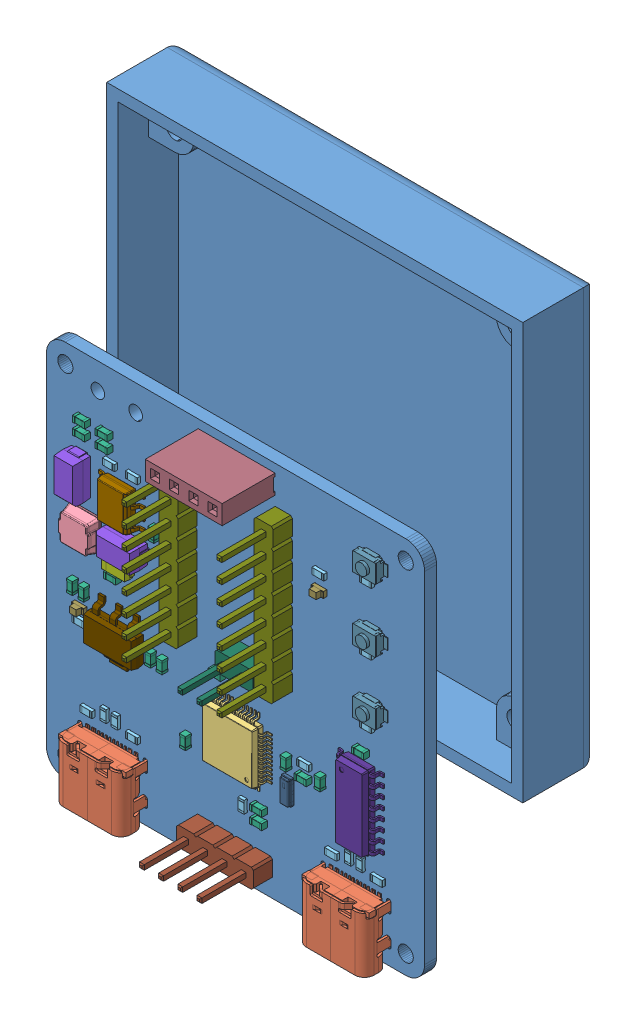
SolidWorks assembly 装配体1, configuration 默认. Lengths in mm.
Overall size (90.8 71.29 67.36).
116 component instances, 19 part files, 0 mates.
Components (placement in the parent):
- Shiled_Bottom-1: Shiled_Bottom [默认] at (-2.6606 -0.7391 50) size (55 55 10)
- TMC2209_TestBoard-2: TMC2209_TestBoard [默认] at (-65.2006 82.5018 107.1928) size (50 50 11.64)
  - TMC2209_TestBoard.step-1: TMC2209_TestBoard.step [默认] at origin size (50 50 11.64)
    - USB_C_Receptacle_GCT_USB4105-xx-A_16P_TopMnt_Horizontal.step-1: USB_C_Receptacle_GCT_USB4105-xx-A_16P_TopMnt_Horizontal.step [默认] at (84.5999 -85.7499 1.63) size (8.94 7.78 4.26)
      - COMPOUND.step-1: COMPOUND.step [默认] at origin size (8.94 7.78 4.26)
    - LQFP-48_7x7mm_P0.5mm.step-1: LQFP-48_7x7mm_P0.5mm.step [默认] at (101.2699 -73.4399 1.63) x (-1 0 0) z (0 0 1) size (9 9 1.5)
      - SOLID.step-1: SOLID.step [默认] at origin size (9 9 1.5)
    - L_Bourns-SRN4018.step-1: L_Bourns-SRN4018.step [默认] at (81.2119 -59.0749 1.63) x (0 -1 0) z (0 0 1) size (4 4.09 1.8)
      - COMPOUND-0.step-1: COMPOUND-0.step [默认] at origin size (4 4.09 1.8)
    - R_0603_1608Metric.step-1: R_0603_1608Metric.step [默认] at (118.4749 -54.7599 1.63) x (-1 0 0) z (0 0 1) size (1.6 0.8 0.45)
      - SOLID-1.step-1: SOLID-1.step [默认] at origin size (1.6 0.8 0.45)
    - C_0603_1608Metric.step-1: C_0603_1608Metric.step [默认] at (80.9149 -46.8999 1.63) x (-1 0 0) z (0 0 1) size (1.6 0.8 0.8)
      - SOLID-2.step-1: SOLID-2.step [默认] at origin size (1.6 0.8 0.8)
    - CP_EIA-3216-10_Kemet-I.step-1: CP_EIA-3216-10_Kemet-I.step [默认] at (85.8749 -60.8899 1.63) size (3.4 1.8 1.2)
      - SOLID-3.step-1: SOLID-3.step [默认] at origin size (3.4 1.8 1.2)
    - C_0603_1608Metric.step-2: C_0603_1608Metric.step [默认] at (90.4899 -55.0149 1.63) x (0 1 0) z (0 0 1) size (1.6 0.8 0.8)
      - SOLID-2.step-1: SOLID-2.step [默认] at origin size (1.6 0.8 0.8)
    - SS54.step-1: SS54.step [默认] at (86.9299 -58.1799 1.63) size (5.1 2.6 2.45)
      - COMPOUND-4.step-1: COMPOUND-4.step [默认] at origin size (5.1 2.6 2.45)
    - TPS5450DDAR.step-1: TPS5450DDAR.step [默认] at (85.9819 -53.7349 1.63) x (-1 0 0) z (0 0 1) size (6.03 4.9 1.57)
      - COMPOUND-5.step-1: COMPOUND-5.step [默认] at origin size (6.03 4.9 1.57)
    - CSTCE8M00G55-R0.step-1: CSTCE8M00G55-R0.step [默认] at (107.9443 -75.8125 1.63) x (0 -1 0) z (-1 0 0) size (3.2 0.7 1.3)
      - COMPOUND-6.step-1: COMPOUND-6.step [默认] at origin size (3.2 0.7 1.3)
    - PinHeader_1x04_P2.54mm_Vertical.step-1: PinHeader_1x04_P2.54mm_Vertical.step [默认] at (96.8849 -85.9399 1.63) x (0 1 0) z (0 0 1) size (2.54 10.16 11.54)
      - SOLID-7.step-1: SOLID-7.step [默认] at origin size (2.54 10.16 11.54)
    - LED_0603_1608Metric.step-1: LED_0603_1608Metric.step [默认] at (80.4824 -68.6399 1.63) size (1.6 0.8 1.1)
      - SOLID-8.step-1: SOLID-8.step [默认] at origin size (1.6 0.8 1.1)
    - R_0603_1608Metric.step-2: R_0603_1608Metric.step [默认] at (119.9149 -80.0649 1.63) x (-1 0 0) z (0 0 1) size (1.6 0.8 0.45)
      - SOLID-1.step-1: SOLID-1.step [默认] at origin size (1.6 0.8 0.45)
    - C_0603_1608Metric.step-3: C_0603_1608Metric.step [默认] at (83.9049 -46.8999 1.63) size (1.6 0.8 0.8)
      - SOLID-2.step-1: SOLID-2.step [默认] at origin size (1.6 0.8 0.8)
    - R_0603_1608Metric.step-3: R_0603_1608Metric.step [默认] at (84.5299 -50.1499 1.63) size (1.6 0.8 0.45)
      - SOLID-1.step-1: SOLID-1.step [默认] at origin size (1.6 0.8 0.45)
    - R_0603_1608Metric.step-4: R_0603_1608Metric.step [默认] at (116.1499 -79.3149 1.63) x (0 -1 0) z (0 0 1) size (1.6 0.8 0.45)
      - SOLID-1.step-1: SOLID-1.step [默认] at origin size (1.6 0.8 0.45)
    - PinSocket_1x04_P2.54mm_Vertical.step-1: PinSocket_1x04_P2.54mm_Vertical.step [默认] at (104.8499 -41.7899 1.63) x (0 -1 0) z (0 0 1) size (2.54 10.16 10.1)
      - SOLID-9.step-1: SOLID-9.step [默认] at origin size (2.54 10.16 10.1)
    - C_0603_1608Metric.step-4: C_0603_1608Metric.step [默认] at (79.7199 -66.3699 1.63) x (0 -1 0) z (0 0 1) size (1.6 0.8 0.8)
      - SOLID-2.step-1: SOLID-2.step [默认] at origin size (1.6 0.8 0.8)
    - B3U-1000P.step-1: B3U-1000P.step [默认] at (119.0699 -60.9299 1.63) x (1 0 0) z (0 -1 0) size (4 1.6 2.5)
      - SOLID-10.step-1: SOLID-10.step [默认] at origin size (4 1.6 2.5)
    - R_0603_1608Metric.step-5: R_0603_1608Metric.step [默认] at (102.0399 -80.4249 1.63) x (0 1 0) z (0 0 1) size (1.6 0.8 0.45)
      - SOLID-1.step-1: SOLID-1.step [默认] at origin size (1.6 0.8 0.45)
    - C_0603_1608Metric.step-5: C_0603_1608Metric.step [默认] at (81.2299 -66.3699 1.63) x (0 -1 0) z (0 0 1) size (1.6 0.8 0.8)
      - SOLID-2.step-1: SOLID-2.step [默认] at origin size (1.6 0.8 0.8)
    - SS54.step-2: SS54.step [默认] at (80.5699 -53.0799 1.63) x (0 1 0) z (0 0 1) size (5.1 2.6 2.45)
      - COMPOUND-4.step-1: COMPOUND-4.step [默认] at origin size (5.1 2.6 2.45)
    - B3U-1000P.step-2: B3U-1000P.step [默认] at (119.0699 -52.6099 1.63) x (1 0 0) z (0 -1 0) size (4 1.6 2.5)
      - SOLID-10.step-1: SOLID-10.step [默认] at origin size (4 1.6 2.5)
    - R_0603_1608Metric.step-6: R_0603_1608Metric.step [默认] at (110.2049 -71.7199 1.63) x (-1 0 0) z (0 0 1) size (1.6 0.8 0.45)
      - SOLID-1.step-1: SOLID-1.step [默认] at origin size (1.6 0.8 0.45)
    - R_0603_1608Metric.step-7: R_0603_1608Metric.step [默认] at (81.5499 -79.9199 1.63) size (1.6 0.8 0.45)
      - SOLID-1.step-1: SOLID-1.step [默认] at origin size (1.6 0.8 0.45)
    - LED_0603_1608Metric.step-2: LED_0603_1608Metric.step [默认] at (112.1799 -50.8199 1.63) x (-1 0 0) z (0 0 1) size (1.6 0.8 1.1)
      - SOLID-8.step-1: SOLID-8.step [默认] at origin size (1.6 0.8 1.1)
    - R_0603_1608Metric.step-8: R_0603_1608Metric.step [默认] at (80.4699 -70.1499 1.63) x (-1 0 0) z (0 0 1) size (1.6 0.8 0.45)
      - SOLID-1.step-1: SOLID-1.step [默认] at origin size (1.6 0.8 0.45)
    - C_0603_1608Metric.step-6: C_0603_1608Metric.step [默认] at (110.2049 -73.2199 1.63) size (1.6 0.8 0.8)
      - SOLID-2.step-1: SOLID-2.step [默认] at origin size (1.6 0.8 0.8)
    - PinHeader_1x02_P2.54mm_Vertical.step-1: PinHeader_1x02_P2.54mm_Vertical.step [默认] at (101.9599 -63.3799 1.63) x (0 1 0) z (0 0 1) size (2.54 5.08 11.54)
      - SOLID-11.step-1: SOLID-11.step [默认] at origin size (2.54 5.08 11.54)
    - USB_C_Receptacle_GCT_USB4105-xx-A_16P_TopMnt_Horizontal.step-2: USB_C_Receptacle_GCT_USB4105-xx-A_16P_TopMnt_Horizontal.step [默认] at (116.7699 -85.7499 1.63) size (8.94 7.78 4.26)
      - COMPOUND.step-1: COMPOUND.step [默认] at origin size (8.94 7.78 4.26)
    - C_0603_1608Metric.step-7: C_0603_1608Metric.step [默认] at (107.9499 -72.4699 1.63) x (0 -1 0) z (0 0 1) size (1.6 0.8 0.8)
      - SOLID-2.step-1: SOLID-2.step [默认] at origin size (1.6 0.8 0.8)
    - C_0603_1608Metric.step-8: C_0603_1608Metric.step [默认] at (91.5699 -69.5099 1.63) x (0 1 0) z (0 0 1) size (1.6 0.8 0.8)
      - SOLID-2.step-1: SOLID-2.step [默认] at origin size (1.6 0.8 0.8)
    - PinHeader_1x08_P2.54mm_Vertical.step-1: PinHeader_1x08_P2.54mm_Vertical.step [默认] at (94.5549 -63.3799 1.63) x (-1 0 0) z (0 0 1) size (2.54 20.32 11.54)
      - SOLID-12.step-1: SOLID-12.step [默认] at origin size (2.54 20.32 11.54)
    - C_0603_1608Metric.step-9: C_0603_1608Metric.step [默认] at (117.8149 -66.3699 1.63) x (-1 0 0) z (0 0 1) size (1.6 0.8 0.8)
      - SOLID-2.step-1: SOLID-2.step [默认] at origin size (1.6 0.8 0.8)
    - PinHeader_1x08_P2.54mm_Vertical.step-2: PinHeader_1x08_P2.54mm_Vertical.step [默认] at (107.1449 -45.5999 1.63) size (2.54 20.32 11.54)
      - SOLID-12.step-1: SOLID-12.step [默认] at origin size (2.54 20.32 11.54)
    - R_0603_1608Metric.step-9: R_0603_1608Metric.step [默认] at (118.4749 -46.5499 1.63) x (-1 0 0) z (0 0 1) size (1.6 0.8 0.45)
      - SOLID-1.step-1: SOLID-1.step [默认] at origin size (1.6 0.8 0.45)
    - C_0603_1608Metric.step-10: C_0603_1608Metric.step [默认] at (94.6599 -76.6499 1.63) x (0 1 0) z (0 0 1) size (1.6 0.8 0.8)
      - SOLID-2.step-1: SOLID-2.step [默认] at origin size (1.6 0.8 0.8)
    - R_0603_1608Metric.step-10: R_0603_1608Metric.step [默认] at (87.5549 -79.9199 1.63) x (-1 0 0) z (0 0 1) size (1.6 0.8 0.45)
      - SOLID-1.step-1: SOLID-1.step [默认] at origin size (1.6 0.8 0.45)
    - R_0603_1608Metric.step-11: R_0603_1608Metric.step [默认] at (83.7999 -79.1699 1.63) x (0 -1 0) z (0 0 1) size (1.6 0.8 0.45)
      - SOLID-1.step-1: SOLID-1.step [默认] at origin size (1.6 0.8 0.45)
    - R_0603_1608Metric.step-12: R_0603_1608Metric.step [默认] at (112.2199 -48.8299 1.63) x (-1 0 0) z (0 0 1) size (1.6 0.8 0.45)
      - SOLID-1.step-1: SOLID-1.step [默认] at origin size (1.6 0.8 0.45)
    - C_0603_1608Metric.step-11: C_0603_1608Metric.step [默认] at (112.4599 -72.4699 1.63) x (0 1 0) z (0 0 1) size (1.6 0.8 0.8)
      - SOLID-2.step-1: SOLID-2.step [默认] at origin size (1.6 0.8 0.8)
    - C_0603_1608Metric.step-12: C_0603_1608Metric.step [默认] at (104.3299 -81.1899 1.63) x (-1 0 0) z (0 0 1) size (1.6 0.8 0.8)
      - SOLID-2.step-1: SOLID-2.step [默认] at origin size (1.6 0.8 0.8)
    - SOIC-16_3.9x9.9mm_P1.27mm.step-1: SOIC-16_3.9x9.9mm_P1.27mm.step [默认] at (117.6099 -72.3099 1.63) size (6 9.9 1.75)
      - SOLID-13.step-1: SOLID-13.step [默认] at origin size (6 9.9 1.75)
    - C_0603_1608Metric.step-13: C_0603_1608Metric.step [默认] at (104.3299 -79.6599 1.63) x (-1 0 0) z (0 0 1) size (1.6 0.8 0.8)
      - SOLID-2.step-1: SOLID-2.step [默认] at origin size (1.6 0.8 0.8)
    - C_0603_1608Metric.step-14: C_0603_1608Metric.step [默认] at (80.9149 -48.3974 1.63) x (-1 0 0) z (0 0 1) size (1.6 0.8 0.8)
      - SOLID-2.step-1: SOLID-2.step [默认] at origin size (1.6 0.8 0.8)
    - R_0603_1608Metric.step-13: R_0603_1608Metric.step [默认] at (85.3099 -79.1699 1.63) x (0 -1 0) z (0 0 1) size (1.6 0.8 0.45)
      - SOLID-1.step-1: SOLID-1.step [默认] at origin size (1.6 0.8 0.45)
    - R_0603_1608Metric.step-14: R_0603_1608Metric.step [默认] at (118.4749 -63.1699 1.63) x (-1 0 0) z (0 0 1) size (1.6 0.8 0.45)
      - SOLID-1.step-1: SOLID-1.step [默认] at origin size (1.6 0.8 0.45)
    - C_0603_1608Metric.step-15: C_0603_1608Metric.step [默认] at (85.0099 -62.7399 1.63) size (1.6 0.8 0.8)
      - SOLID-2.step-1: SOLID-2.step [默认] at origin size (1.6 0.8 0.8)
    - SOT-223.step-1: SOT-223.step [默认] at (85.6599 -69.2899 1.63) x (0 -1 0) z (0 0 1) size (7 6.5 1.7)
      - SOLID-14.step-1: SOLID-14.step [默认] at origin size (7 6.5 1.7)
    - C_0603_1608Metric.step-16: C_0603_1608Metric.step [默认] at (98.8599 -66.8599 1.63) size (1.6 0.8 0.8)
      - SOLID-2.step-1: SOLID-2.step [默认] at origin size (1.6 0.8 0.8)
    - C_0603_1608Metric.step-17: C_0603_1608Metric.step [默认] at (83.9049 -48.3974 1.63) size (1.6 0.8 0.8)
      - SOLID-2.step-1: SOLID-2.step [默认] at origin size (1.6 0.8 0.8)
    - C_0603_1608Metric.step-18: C_0603_1608Metric.step [默认] at (90.0499 -69.5099 1.63) x (0 1 0) z (0 0 1) size (1.6 0.8 0.8)
      - SOLID-2.step-1: SOLID-2.step [默认] at origin size (1.6 0.8 0.8)
    - R_0603_1608Metric.step-15: R_0603_1608Metric.step [默认] at (87.5449 -50.1499 1.63) size (1.6 0.8 0.45)
      - SOLID-1.step-1: SOLID-1.step [默认] at origin size (1.6 0.8 0.45)
    - B3U-1000P.step-3: B3U-1000P.step [默认] at (119.0699 -44.2699 1.63) x (1 0 0) z (0 -1 0) size (4 1.6 2.5)
      - SOLID-10.step-1: SOLID-10.step [默认] at origin size (4 1.6 2.5)
    - R_0603_1608Metric.step-16: R_0603_1608Metric.step [默认] at (117.6599 -79.3149 1.63) x (0 -1 0) z (0 0 1) size (1.6 0.8 0.45)
      - SOLID-1.step-1: SOLID-1.step [默认] at origin size (1.6 0.8 0.45)
    - R_0603_1608Metric.step-17: R_0603_1608Metric.step [默认] at (113.8899 -80.0649 1.63) size (1.6 0.8 0.45)
      - SOLID-1.step-1: SOLID-1.step [默认] at origin size (1.6 0.8 0.45)
    - TMC2209_TestBoard PCB.step-1: TMC2209_TestBoard PCB.step [默认] at origin size (50 50 1.58)
